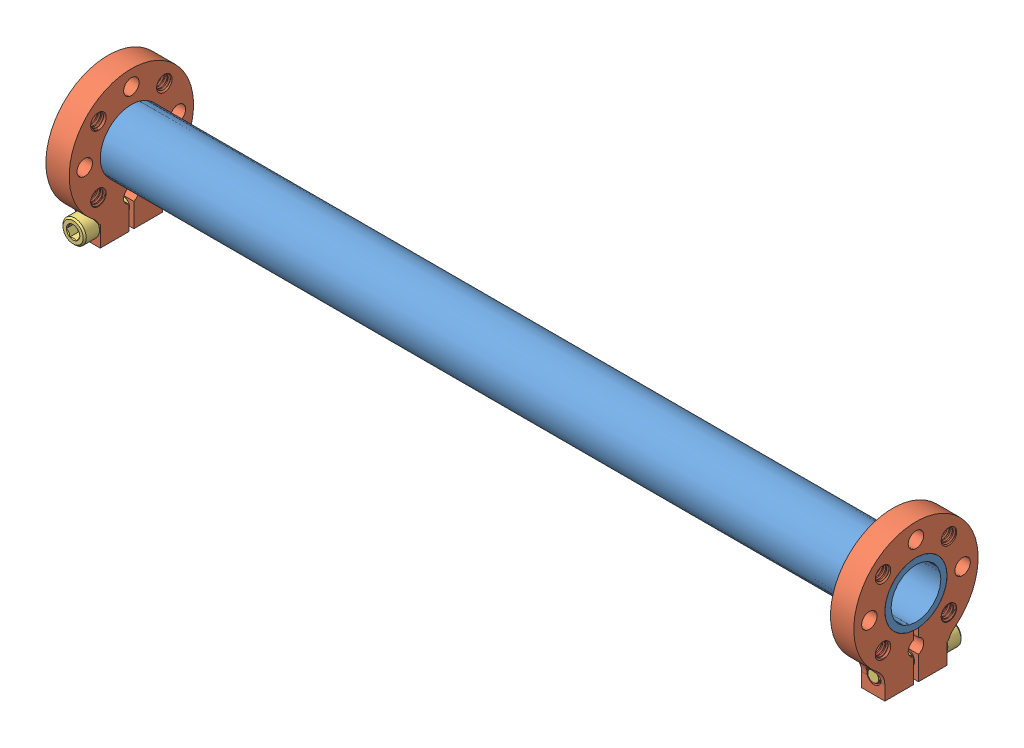
SolidWorks assembly subassem_rightlink, configuration Default. Lengths in mm.
Overall size (330.59 60.57 50.8).
7 component instances, 3 part files, 6 mates.
Components (placement in the parent):
- tubing1rl-1: tubing1rl [Default<As Machined>] at (32.4558 163.244 220.4128) size (330.2 25.4 25.4)
- Clamping hub 1inch-1: Clamping hub 1inch [Default] at (14.6195 139.1097 289.2058) x (0 0 1) z (0 1 0) size (50.8 9.91 57.17)
  - 545356-1: 545356 [Default] at (-68.793 17.8362 24.1343) size (50.8 9.91 57.17)
  - 91251A542_91251A542-1: 91251A542_91251A542 [Default] at (-81.493 22.5987 -1.2123) x (0 0 1) z (-1 0 0) size (9.53 9.53 32.08)
- Clamping hub 1inch-2: Clamping hub 1inch [Default] at (380.492 139.1097 151.6198) x (0 0 -1) z (0 1 0) size (50.8 9.91 57.17)
  - 545356-1: 545356 [Default] at (-68.793 17.8362 24.1343) size (50.8 9.91 57.17)
  - 91251A542_91251A542-1: 91251A542_91251A542 [Default] at (-81.493 22.5987 -1.2123) x (0 0 1) z (-1 0 0) size (9.53 9.53 32.08)
Mates (geometry in assembly coordinates):
- Concentric1: concentric anti-aligned: circle of tubing1rl-1; cylinder of Clamping hub 1inch-1/545356-1 through (41.9808 163.244 220.4128) axis (-1 0 0) radius 12.7
- Parallel1: parallel anti-aligned: line of Clamping hub 1inch-1/545356-1 through (32.4558 141.186 219.3968) axis (0 -1 0); line of assembly
- Coincident4: coincident aligned: plane of tubing1rl-1 through (32.4558 163.244 220.4128) normal (-1 0 0); plane of Clamping hub 1inch-1/545356-1 through (32.4558 163.244 220.4128) normal (-1 0 0)
- Concentric2: concentric anti-aligned: cylinder of tubing1rl-1 through (362.6558 163.244 220.4128) axis (-1 0 0) radius 12.7; cylinder of Clamping hub 1inch-2/545356-1 through (353.1308 163.244 220.4128) axis (1 0 0) radius 12.7
- Parallel2: parallel anti-aligned: line of Clamping hub 1inch-1/545356-1 through (41.9808 141.186 219.3968) axis (0 -1 0); line of Clamping hub 1inch-2/545356-1 through (362.6558 131.4712 219.3968) axis (0 1 0)
- Coincident5: coincident aligned: plane of tubing1rl-1 through (362.6558 163.244 220.4128) normal (1 0 0); plane of Clamping hub 1inch-2/545356-1 through (362.6558 163.244 220.4128) normal (1 0 0)
